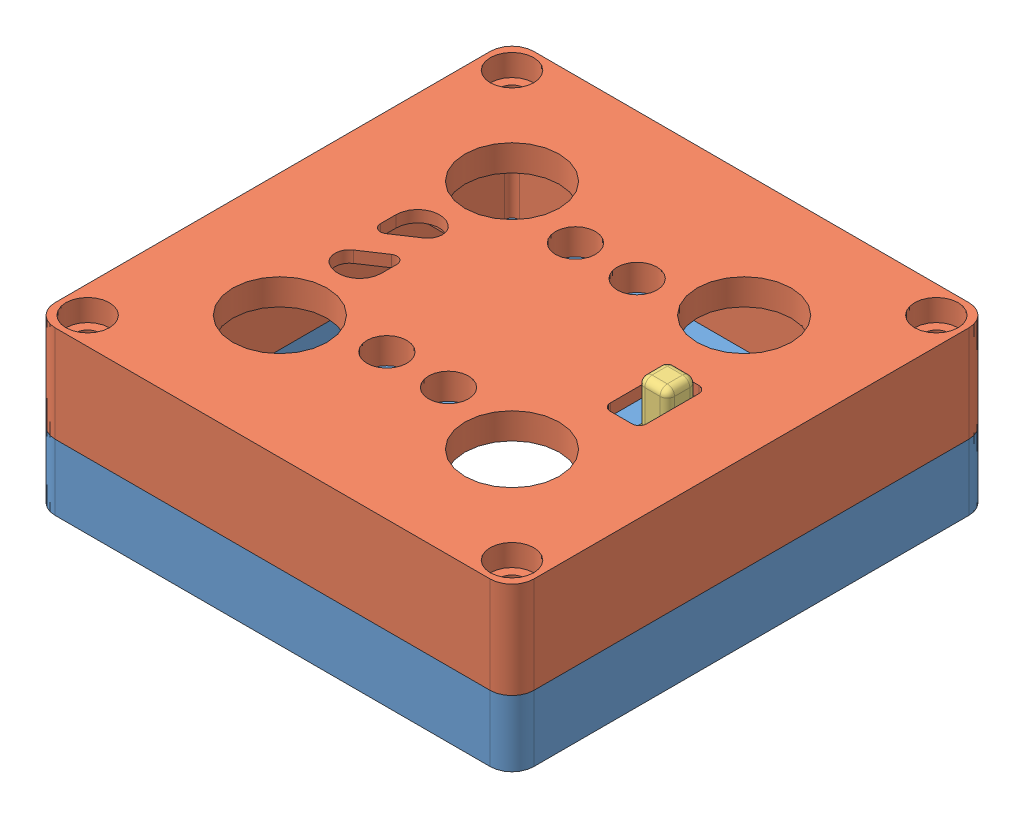
SolidWorks assembly Case v2, configuration Default. Lengths in mm.
Overall size (66 24.24 66).
3 component instances, 3 part files, 3 mates.
Components (placement in the parent):
- Bottom-1: Bottom [Default] at origin size (66 9.1 66)
- Lid-1: Lid [Default<As Machined>] at (-14.992 10.9 1.8359) size (66 13.3 66)
- On off slider-1: On off slider [Default] at (3.7179 16.1887 9.9936) x (-0.000108 -0.004926 0.999988) z (-0.999992 0.003888 -0.000089) size (14 8 6)
Mates (geometry in assembly coordinates):
- Coincident2: coincident anti-aligned: plane of Bottom-1 through (0 9.1 0) normal (0 1 0); plane of Lid-1 through (-14.992 9.1 1.8359) normal (0 -1 0)
- Coincident3: coincident aligned: plane of Bottom-1 through (-49.1586 9.1 43.1276) normal (0 0 1); plane of Lid-1 through (-14.992 10.9 43.1276) normal (0 0 1)
- Coincident4: coincident aligned: plane of Bottom-1 through (-49.1586 9.1 -22.8724) normal (-1 0 0); plane of Lid-1 through (-49.1586 10.9 1.8359) normal (-1 0 0)
